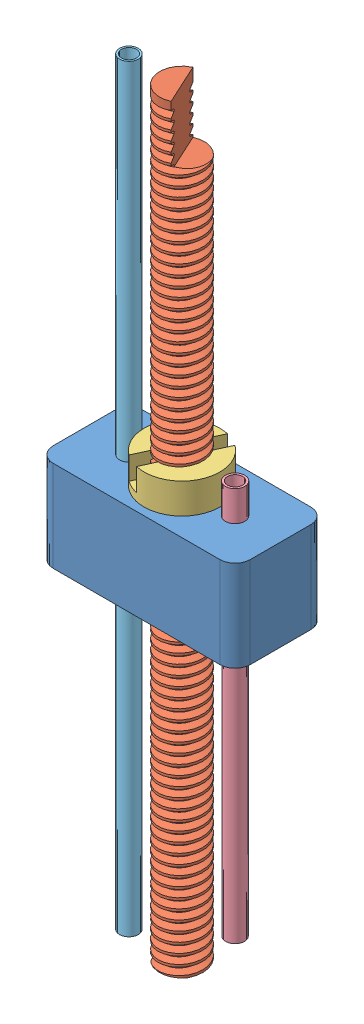
SolidWorks assembly ShuttleAssembly, configuration Default. Lengths in mm.
Overall size (6.5 25.22 3.31).
5 component instances, 5 part files, 7 mates.
Components (placement in the parent):
- Shuttle-1: Shuttle [Default] at (2.5582 1.9761 5.5221) size (6.5 3 3)
- Threaded Rod 25mm-1: Threaded Rod 25mm [Default] at (2.5582 -8.5786 5.5221) x (0.813094 0 0.582132) z (-0.582132 0 0.813094) size (1.64 25.22 1.64)
- Grooved Nut-1: Grooved Nut [Default] at (2.5582 1.9761 5.5221) x (0.414361 0 -0.910113) z (0.910113 0 0.414361) size (2.5 4 2.5)
- 23g Tubing 13mm-1: 23g Tubing 13mm [Default] at (4.3082 -7.0239 5.5221) size (0.64 13 0.64)
- 23g Tubing 25mm-1: 23g Tubing 25mm [Default] at (0.8082 -8.5786 5.5221) size (0.62 25 0.62)
Mates (geometry in assembly coordinates):
- Coincident1: coincident aligned: plane of Shuttle-1 through (2.5582 1.9761 5.5221) normal (0 -1 0); plane of Grooved Nut-1 through (2.5582 1.9761 5.5221) normal (0 -1 0)
- Concentric1: concentric anti-aligned: circle of Shuttle-1; circle of Grooved Nut-1
- Concentric2: concentric aligned: circle of Shuttle-1; circle of 23g Tubing 13mm-1
- Distance1: distance = 1 mm aligned: plane of 23g Tubing 13mm-1 through (4.3082 5.9761 5.5221) normal (0 1 0); plane of Shuttle-1 through (2.5582 4.9761 5.5221) normal (0 1 0)
- Concentric3: concentric aligned: circle of Shuttle-1; circle of 23g Tubing 25mm-1
- Concentric4: concentric aligned: circle of Shuttle-1; circle of Threaded Rod 25mm-1
- Distance2: distance = 0 mm aligned: plane of Threaded Rod 25mm-1 through (2.5582 -8.5786 5.5221) normal (0 -1 0); plane of 23g Tubing 25mm-1 through (0.8082 -8.5786 5.5221) normal (0 -1 0)
